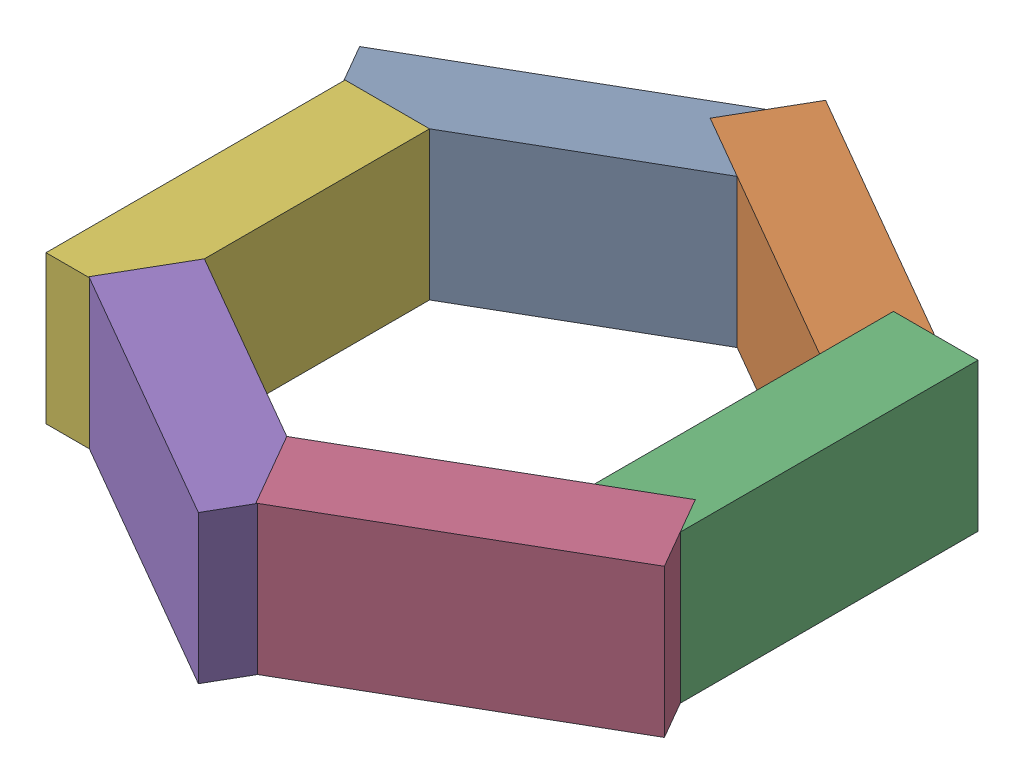
SolidWorks assembly СлойГР, configuration По умолчанию. Lengths in mm.
Overall size (463.37 114 515.79).
6 component instances, 1 part files, 3 mates.
Components (placement in the parent):
- К_огнеуп-1: К_огнеуп [По умолчанию] at (0 0 -173.2051) x (-0.866025 0 0.5) z (0 -1 0) size (230 65 114)
- К_огнеуп-2: К_огнеуп [По умолчанию] at (150 0 -86.6025) x (-0.866025 0 -0.5) z (0 -1 0) size (230 65 114)
- К_огнеуп-3: К_огнеуп [По умолчанию] at (150 0 86.6025) x (0 0 -1) z (0 -1 0) size (230 65 114)
- К_огнеуп-4: К_огнеуп [По умолчанию] at (0 0 173.2051) x (0.866025 0 -0.5) z (0 -1 0) size (230 65 114)
- К_огнеуп-5: К_огнеуп [По умолчанию] at (-150 0 86.6025) x (0.866025 0 0.5) z (0 -1 0) size (230 65 114)
- К_огнеуп-6: К_огнеуп [По умолчанию] at (-150 0 -86.6025) x (0 0 1) z (0 -1 0) size (230 65 114)
Mates (geometry in assembly coordinates):
- Совпадение1: coincident anti-aligned: plane of К_огнеуп-1 through (-32.5 0 -229.4967) normal (0 -1 0)
- Совпадение2: coincident: point of К_огнеуп-1
- Совпадение3: coincident aligned: line of К_огнеуп-1 through (0 0 -173.2051) axis (-0.866025 0 0.5)
